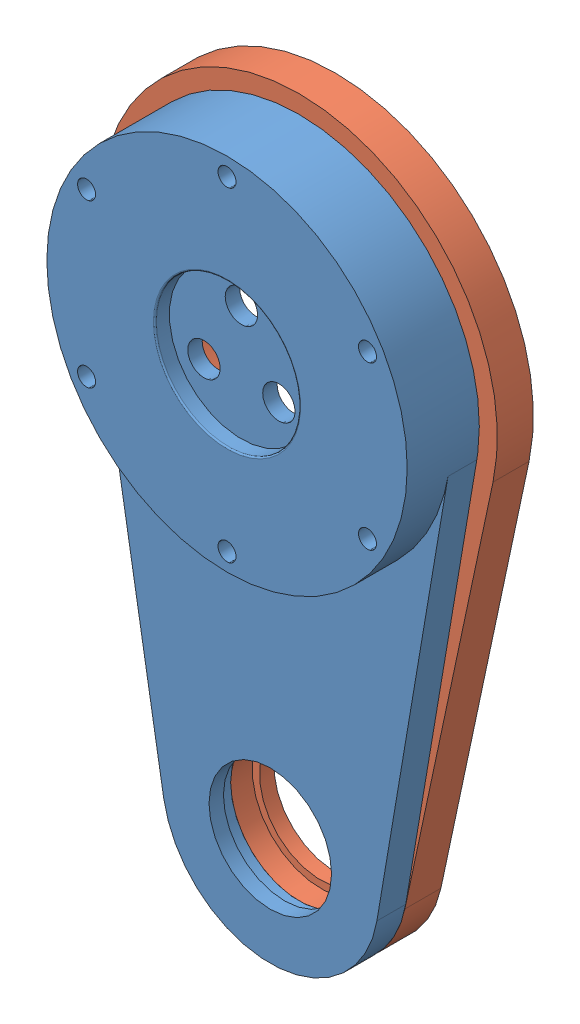
SolidWorks assembly knee_link_v2_assem, configuration 기본. Lengths in mm.
Overall size (55 102.5 15).
2 component instances, 2 part files, 3 mates.
Components (placement in the parent):
- Knee Link v2_part1-1: Knee Link v2_part1 [기본] at origin size (50 100 10)
- Knee Link v2_part2-1: Knee Link v2_part2 [기본] at (0 0 -2) size (55 102.5 5)
Mates (geometry in assembly coordinates):
- 동심3: concentric anti-aligned: cylinder of Knee Link v2_part1-1 through (0 0 -4) axis (0 0 1) radius 25; cylinder of Knee Link v2_part2-1 through (0 0 -7) axis (0 0 -1) radius 18.5
- 동심4: concentric aligned: cylinder of Knee Link v2_part1-1 through (0 -60 -13) axis (0 0 1) radius 9.5; cylinder of Knee Link v2_part2-1 through (0 -60 -13) axis (0 0 1) radius 9.5
- 일치2: coincident anti-aligned: plane of Knee Link v2_part1-1 through (-35.5676 -176.5 -10) normal (0 0 -1); plane of Knee Link v2_part2-1 through (-35.5676 -176.5 -10) normal (0 0 1)
